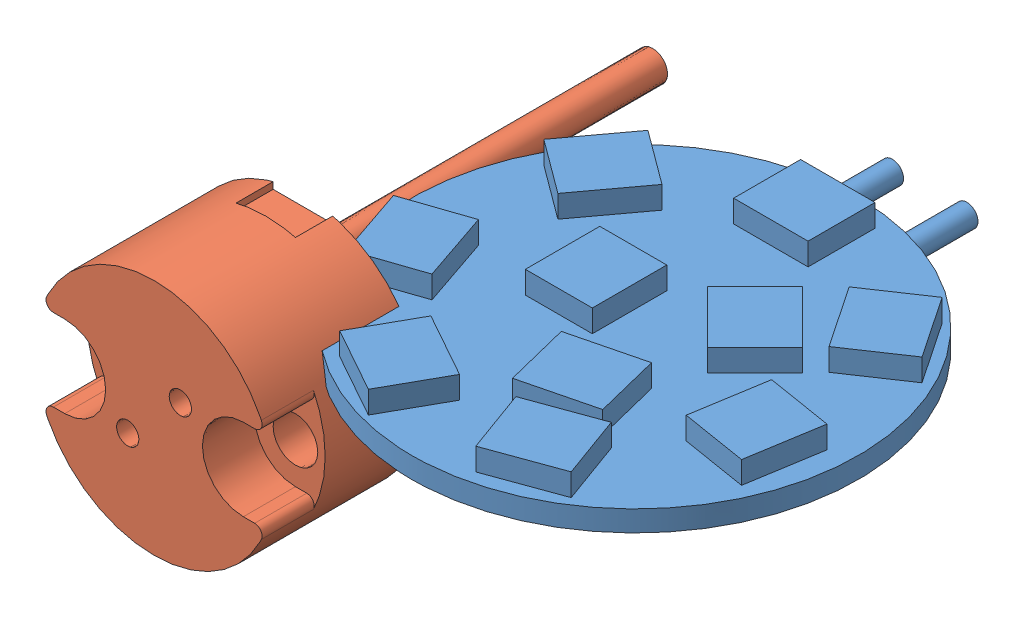
SolidWorks assembly Baugruppe1, configuration Standard. Lengths in mm.
Overall size (38.57 16 36.54).
2 component instances, 2 part files, 0 mates.
Components (placement in the parent):
- G4 LED-1: G4 LED [Standard] at (-0.3566 -2.4382 37.1777) size (30 4.4 34.79)
- G4 Sockel-1: G4 Sockel [Standard] at (-15.9263 -5.7569 43.9277) size (16 16 33.5)
